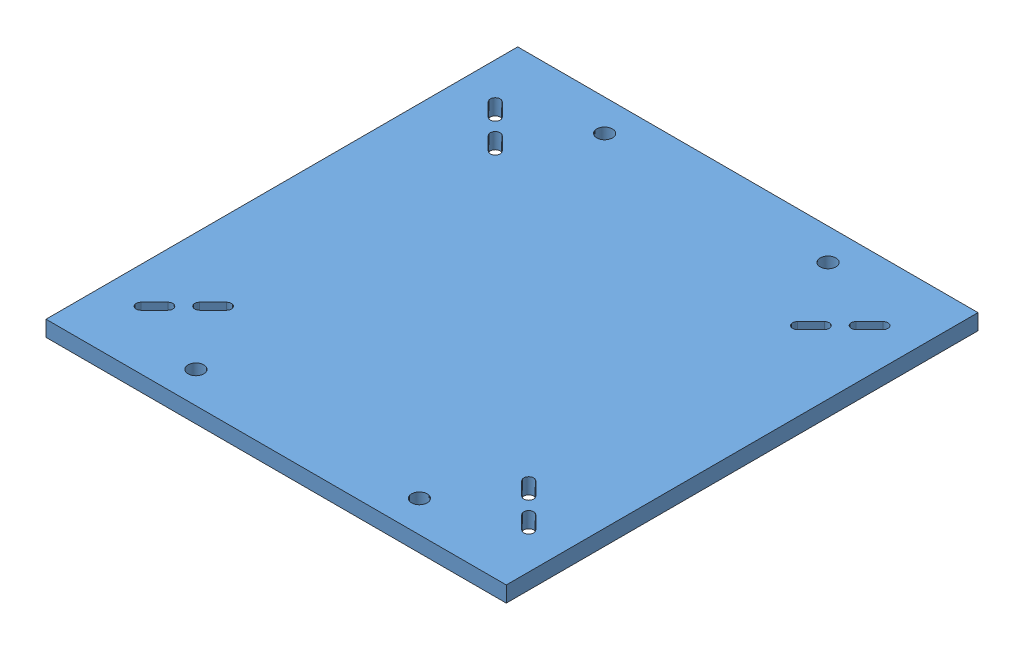
SolidWorks assembly OreSat Holder Assembly, configuration Default. Lengths in mm.
Overall size (185.4 6.35 190).
5 component instances, 1 part files, 15 mates.
Components (placement in the parent):
- OreSat Holder Plate-1: OreSat Holder Plate [Default] at (-92.7 0 -95) size (185.4 6.35 190)
- Clamp and Fastener Assembly^OreSat Holder Assembly-1: Clamp and Fastener Assembly^OreSat Holder Assembly [Default] at (-90.8976 0 -73.3713) x (0.707107 0 0.707107) z (-0.707107 0 0.707107) (suppressed, hidden, virtual)
- Clamp and Fastener Assembly^OreSat Holder Assembly-3: Clamp and Fastener Assembly^OreSat Holder Assembly [Default] at (80.1213 0 -84.1476) x (-0.707107 0 0.707107) z (-0.707107 0 -0.707107) (suppressed, hidden, virtual)
- Clamp and Fastener Assembly^OreSat Holder Assembly-4: Clamp and Fastener Assembly^OreSat Holder Assembly [Default] at (90.8976 0 73.3713) x (-0.707107 0 -0.707107) z (0.707107 0 -0.707107) (suppressed, hidden, virtual)
- Clamp and Fastener Assembly^OreSat Holder Assembly-5: Clamp and Fastener Assembly^OreSat Holder Assembly [Default] at (-80.1213 0 84.1476) x (0.707107 0 -0.707107) z (0.707107 0 0.707107) (suppressed, hidden, virtual)
Mates (geometry in assembly coordinates):
- Coincident1: coincident aligned: plane of OreSat Holder Plate-1 through (-92.7 0 -95) normal (0 1 0)
- Coincident2: coincident: line of OreSat Holder Plate-1 through (0 0 -95) axis (0 0 1)
- Coincident3: coincident: line of OreSat Holder Plate-1 through (0 185.4 -92.7) axis (0 0 1)
- Coincident4: coincident anti-aligned: plane of OreSat Holder Plate-1 through (-92.7 0 -95) normal (0 1 0); plane of Clamp and Fastener Assembly^OreSat Holder Assembly-1/clampJig-1 through (-80.1213 0 -84.1476) normal (0 -1 0)
- Coincident5: coincident anti-aligned: plane of OreSat Holder Plate-1 through (-92.7 0 -95) normal (0 1 0); plane of Clamp and Fastener Assembly^OreSat Holder Assembly-3/clampJig-1 through (90.8976 0 -73.3713) normal (0 -1 0)
- Coincident6: coincident anti-aligned: plane of OreSat Holder Plate-1 through (-92.7 0 -95) normal (0 1 0); plane of Clamp and Fastener Assembly^OreSat Holder Assembly-4/clampJig-1 through (80.1213 0 84.1476) normal (0 -1 0)
- Coincident7: coincident anti-aligned: plane of OreSat Holder Plate-1 through (-92.7 0 -95) normal (0 1 0); plane of Clamp and Fastener Assembly^OreSat Holder Assembly-5/clampJig-1 through (-90.8976 0 73.3713) normal (0 -1 0)
- Slot1: slot anti-aligned: cylinder of ? through (60.8809 18.38 54.1309) axis (0 -1 0) radius 1.5; plane of OreSat Holder Plate-1 through (-89.0608 -6.35 -98.6392) normal (-0.707107 0 0.707107); cylinder of ? through (60.8809 -6.35 49.1309) axis (0 1 0) radius 2
- Slot2: slot anti-aligned: cylinder of ? through (78.0778 18.38 71.3278) axis (0 -1 0) radius 1.5; plane of OreSat Holder Plate-1 through (-89.0608 -6.35 -98.6392) normal (-0.707107 0 0.707107); cylinder of ? through (72.6896 -6.35 60.9396) axis (0 1 0) radius 2
- Slot3: slot anti-aligned: cylinder of ? through (60.8809 18.38 -54.1309) axis (0 -1 0) radius 1.5; plane of OreSat Holder Plate-1 through (3.1108 -6.35 0.8108) normal (0.707107 0 0.707107); cylinder of ? through (60.8809 -6.35 -59.1309) axis (0 1 0) radius 2
- Slot4: slot anti-aligned: cylinder of ? through (78.0778 18.38 -71.3278) axis (0 -1 0) radius 1.5; plane of OreSat Holder Plate-1 through (5.9392 -6.35 3.6392) normal (-0.707107 0 -0.707107); cylinder of ? through (78.0778 -6.35 -76.3278) axis (0 1 0) radius 2
- Slot5: slot anti-aligned: cylinder of ? through (-60.8809 18.38 -54.1309) axis (0 -1 0) radius 1.5; plane of OreSat Holder Plate-1 through (-59.4667 -6.35 -55.5451) normal (-0.707107 0 0.707107); cylinder of ? through (-66.2691 -6.35 -64.5191) axis (0 1 0) radius 2
- Slot6: slot anti-aligned: cylinder of ? through (-78.0778 18.38 -71.3278) axis (0 -1 0) radius 1.5; plane of OreSat Holder Plate-1 through (-95.8108 -6.35 -91.8892) normal (-0.707107 0 0.707107); cylinder of ? through (-78.0778 -6.35 -76.3278) axis (0 1 0) radius 2
- Slot7: slot anti-aligned: cylinder of ? through (-60.8809 18.38 54.1309) axis (0 -1 0) radius 1.5; plane of OreSat Holder Plate-1 through (-62.2951 -6.35 52.7167) normal (0.707107 0 0.707107); cylinder of ? through (-66.2691 -6.35 54.5191) axis (0 1 0) radius 2
- Slot8: slot anti-aligned: cylinder of ? through (-78.0778 18.38 71.3278) axis (0 -1 0) radius 1.5; plane of OreSat Holder Plate-1 through (-79.492 -6.35 69.9135) normal (0.707107 0 0.707107); cylinder of ? through (-78.0778 -6.35 66.3278) axis (0 1 0) radius 2
